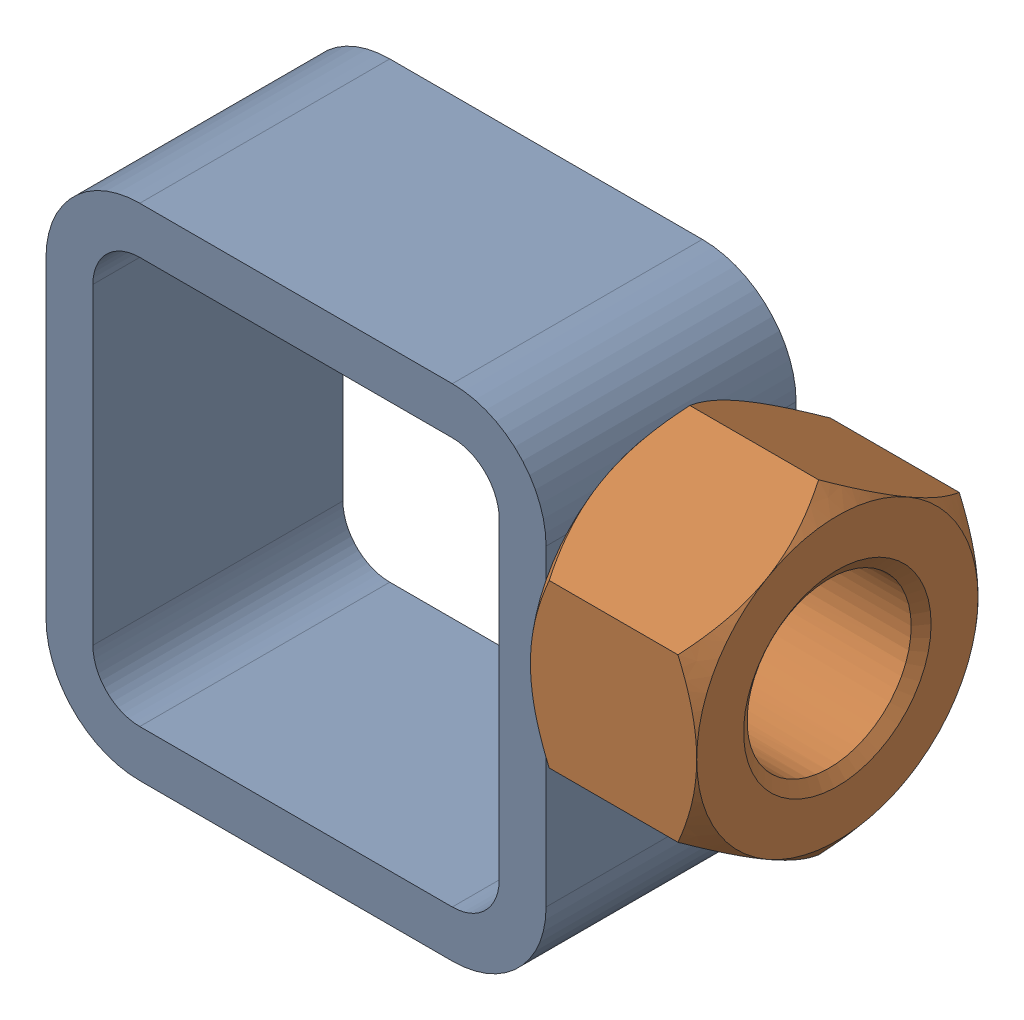
SolidWorks assembly 01-005-00-0-4, configuration Default. Lengths in mm.
Overall size (67.69 50.8 28.57).
2 component instances, 2 part files, 0 mates.
Components (placement in the parent):
- tube square_ai(PreviewCfg)-1: tube square_ai(PreviewCfg) [Default] at origin size (50.8 50.8 25.4)
- hex nut_ai(HNUT 0.7500-10-D-C)-1: hex nut_ai(HNUT 0.7500-10-D-C) [Default] at (67.691 31.75 0) x (0 0 -1) z (1 0 0) size (28.57 33 16.89)
